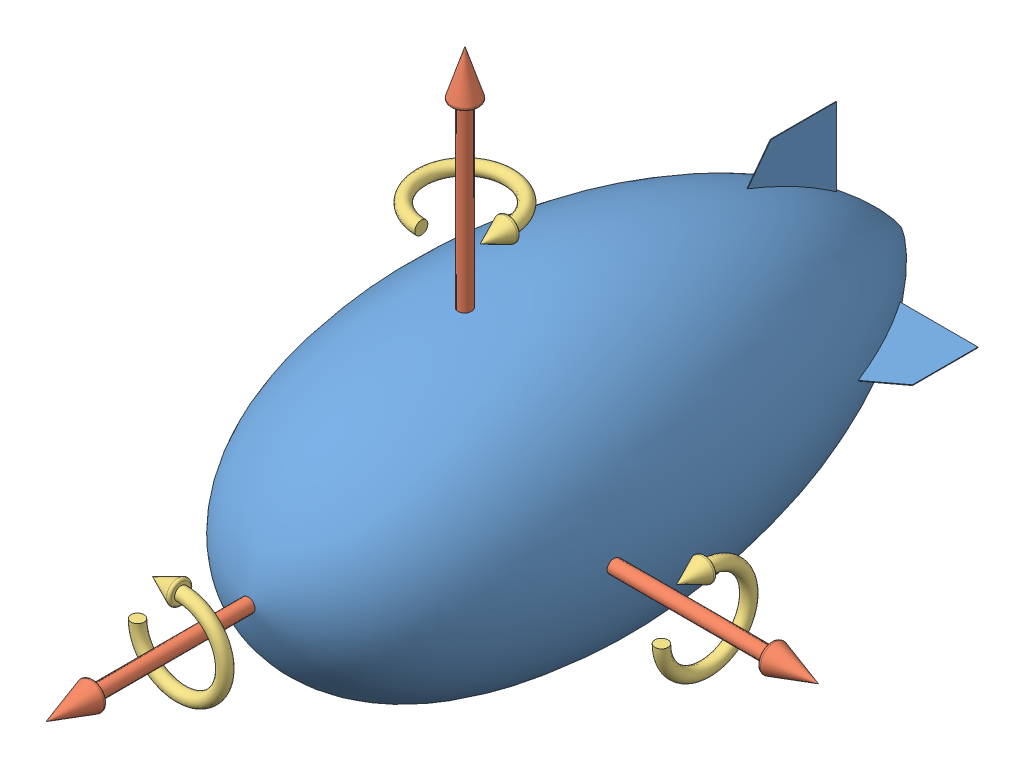
SolidWorks assembly AXIS, configuration Default. Lengths in mm.
Overall size (2557.18 2657.18 3919.18).
7 component instances, 3 part files, 21 mates.
Components (placement in the parent):
- envelope-1: envelope [Default] at origin size (1876.01 1876.01 3000)
- arrow-1: arrow [Default] at (0 0 -300) size (128.36 128.36 1219.18)
- arrow-2: arrow [Default] at (0 500 -1000) x (1 0 0) z (0 1 0) size (128.36 128.36 1219.18)
- arrow-3: arrow [Default] at (400 0 -1000) x (0 0 -1) z (1 0 0) size (128.36 128.36 1219.18)
- arrow_rot-1: arrow_rot [Default] at (0 0 300) x (1 0 0) z (0 -1 0) size (460 108.84 484.42)
- arrow_rot-2: arrow_rot [Default] at (1100 0 -1000) x (0 0 -1) z (0 -1 0) size (460 108.84 484.42)
- arrow_rot-3: arrow_rot [Default] at (0 1100 -1000) x (0 0 -1) z (-1 0 0) size (460 108.84 484.42)
Mates (geometry in assembly coordinates):
- Coincident1: coincident aligned: plane of envelope-1 through (0 0 0) normal (0 0 1); plane of assembly
- Coincident2: coincident aligned: plane of envelope-1 through (0 0 0) normal (0 1 0); plane of assembly
- Coincident3: coincident aligned: plane of envelope-1 through (0 0 0) normal (1 0 0); plane of assembly
- Coincident4: coincident aligned: plane of arrow-1 through (0 0 -300) normal (0 1 0); plane of assembly
- Coincident5: coincident aligned: plane of arrow-1 through (0 0 -300) normal (1 0 0); plane of assembly
- Distance1: distance = 1000 mm anti-aligned: plane of arrow-2 through (0 500 -1000) normal (0 0 -1); plane of assembly
- Distance2: distance = 500 mm aligned: plane of arrow-2 through (0 500 -1000) normal (0 1 0); plane of assembly
- Coincident8: coincident aligned: plane of arrow-2; plane of assembly
- Distance3: distance = 300 mm aligned: plane of arrow-1 through (0 0 -300) normal (0 0 1); plane of assembly
- Coincident11: coincident aligned: plane of arrow-3; plane of assembly
- Coincident12: coincident aligned: plane of arrow-2 through (0 500 -1000) normal (0 0 -1); plane of arrow-3 through (400 0 -1000) normal (0 0 -1)
- Distance4: distance = 400 mm aligned: plane of assembly; plane of arrow-3 through (400 0 -1000) normal (1 0 0)
- Coincident14: coincident anti-aligned: plane of arrow_rot-1 through (0 0 300) normal (0 -1 0); plane of assembly
- Distance5: distance = 300 mm aligned: plane of arrow_rot-1 through (0 0 300) normal (0 0 1); plane of assembly
- Coincident16: coincident aligned: plane of arrow_rot-1; plane of assembly
- Coincident17: coincident anti-aligned: plane of ? through (-1100 0 -1000) normal (0 -1 0)
- Distance6: distance = 1100 mm aligned: plane of arrow_rot-2; plane of assembly
- Coincident19: coincident aligned: plane of arrow-2 through (0 500 -1000) normal (0 0 -1); plane of arrow_rot-2
- Distance7: distance = 1100 mm anti-aligned: plane of arrow_rot-3; plane of assembly
- Coincident20: coincident aligned: plane of arrow_rot-3 through (0 1100 -800) normal (1 0 0); plane of assembly
- Coincident23: coincident aligned: plane of arrow-2 through (0 500 -1000) normal (0 0 -1); plane of arrow_rot-3
